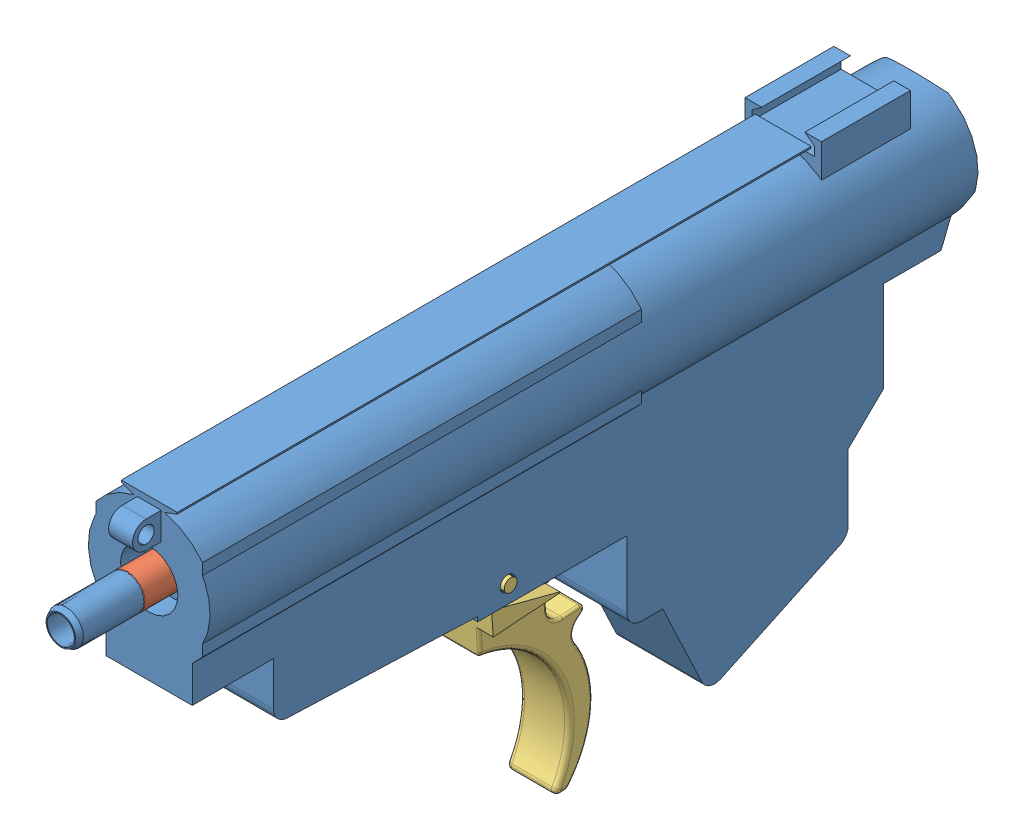
SolidWorks assembly NBB Box Nr1, configuration Standard. Lengths in mm.
Overall size (25.5 95.08 179.1).
6 component instances, 6 part files, 5 mates.
Components (placement in the parent):
- V3 GB mit allen wichtigen maßen-1: V3 GB mit allen wichtigen maßen [Standard] at (-8.9075 3.8216 0) size (25.5 86.02 179.1)
- G36 Nozzle-1: G36 Nozzle [Standard] at (3.8425 21.6759 50.3811) size (9 9 24.2)
- G36 Abzug-1: G36 Abzug [Standard] at (-2.9575 -5.0087 -50.8187) x (1 0 0) z (0 -0.073513 0.997294) size (19 51.7 22)
- NBB Gasrohr-1: NBB Gasrohr [Standard] at origin size (6 6 155)
- NBB Abzugstrebe-2: NBB Abzugstrebe [Standard] at (0.3 0.0008 0.0066) x (1 0 0) z (0 -0.000869 1) size (10.5 44.39 13.15)
- NBB Gasrohrmantel für Nozzle-1: NBB Gasrohrmantel für Nozzle [Standard] at origin size (8 8 51)
Mates (geometry in assembly coordinates):
- Sperren3: lock: unknown of ?; unknown of ?
- Konzentrisch8: concentric anti-aligned: cylinder of V3 GB mit allen wichtigen maßen-1 through (-13.1575 -7.6241 0.8811) axis (1 0 0) radius 1.6; cylinder of G36 Abzug-1 through (13.4425 -7.6241 0.8811) axis (-1 0 0) radius 1.35
- Abstand2: distance = 0.6 mm aligned: plane of G36 Abzug-1 through (13.4425 -7.6241 0.8811) normal (1 0 0); plane of V3 GB mit allen wichtigen maßen-1 through (12.8425 -47.8241 -93.7189) normal (1 0 0)
- Konzentrisch9: concentric aligned: cylinder of G36 Nozzle-1 through (3.8425 21.6759 82.8569) axis (0 0 1) radius 2.675; cylinder of NBB Gasrohr-1 through (3.8425 21.6759 -88.1189) axis (0 0 1) radius 3
- Abstand3: distance = 14.5 mm aligned: plane of G36 Nozzle-1 through (3.8425 26.1759 52.3811) normal (0 0 1); plane of V3 GB mit allen wichtigen maßen-1 through (16.5925 36.6759 66.8811) normal (0 0 1)
